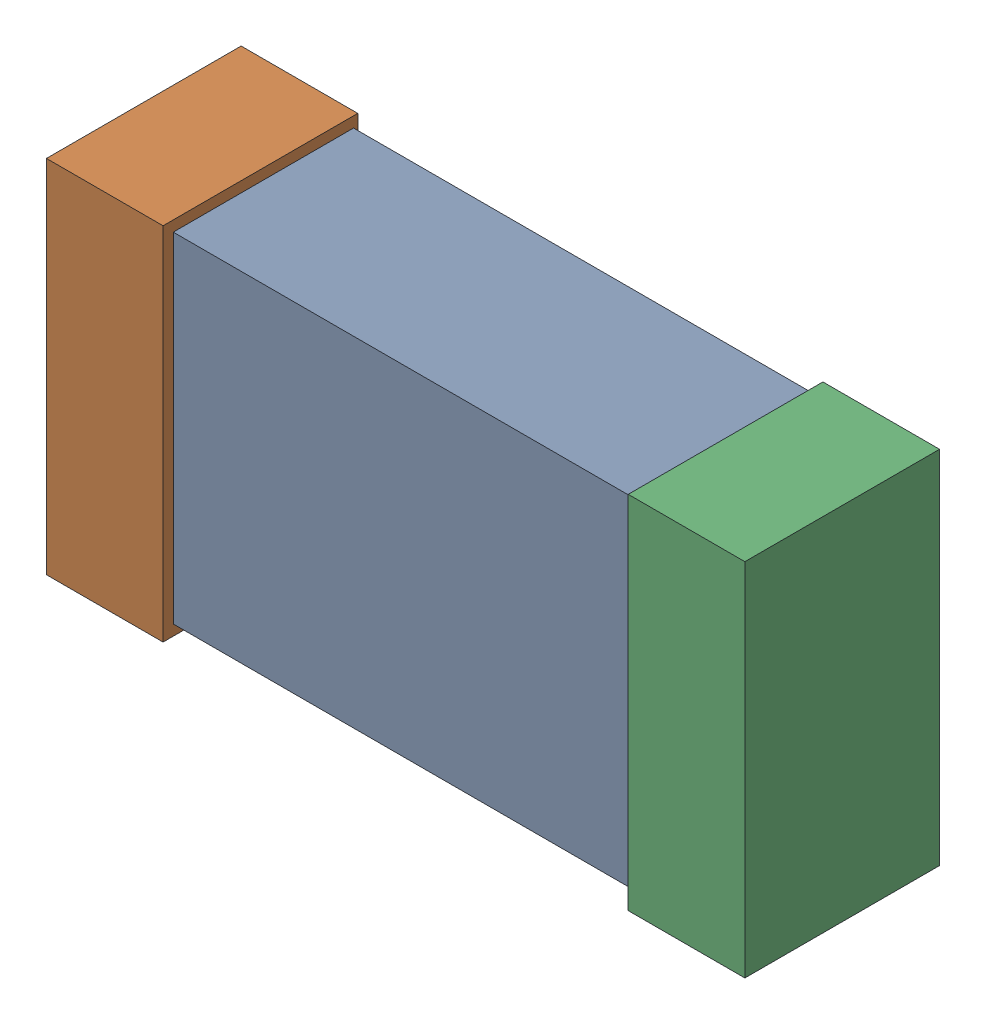
SolidWorks assembly R29, configuration Default. Lengths in mm.
Overall size (1.65 0.85 0.46).
6 component instances, 2 part files, 0 mates.
Components (placement in the parent):
- 432120720_23-1: 432120720_23 [Default] at (22.4266 22.0499 -0.8615) size (1.5 0.8 0.42)
  - Extruded (12)-1: Extruded (12) [Default] at origin size (1.5 0.8 0.42)
- 432120464_48-1: 432120464_48 [Default] at (21.7408 22.0499 -0.8715) size (0.28 0.85 0.46)
  - Extruded (11)-1: Extruded (11) [Default] at origin size (0.28 0.85 0.46)
- 432120464_49-1: 432120464_49 [Default] at (23.1123 22.0499 -0.8715) size (0.28 0.85 0.46)
  - Extruded (11)-1: Extruded (11) [Default] at origin size (0.28 0.85 0.46)
